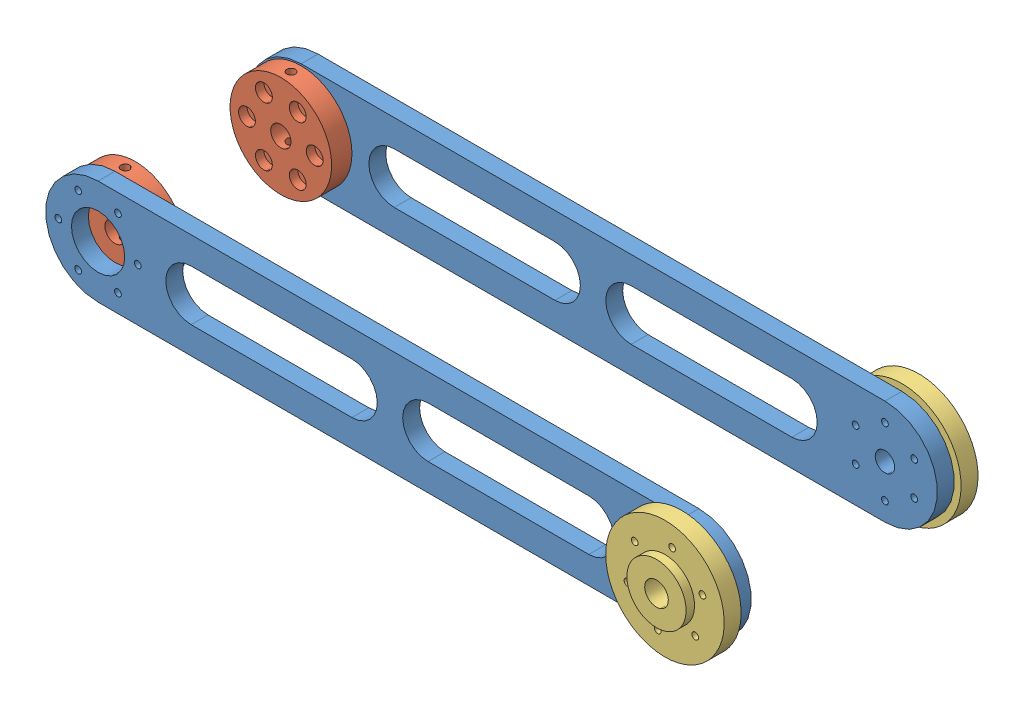
SolidWorks assembly khau2, configuration Default. Lengths in mm.
Overall size (425.35 98.68 160).
6 component instances, 3 part files, 11 mates.
Components (placement in the parent):
- khau2-1: khau2 [Default] at (105.1973 25.4543 -70.4266) x (1 -0.000341 0) z (-0.000341 -1 0) size (407 10 62)
- khau2-2: khau2 [Default] at (105.1973 25.4543 59.5734) x (1 -0.000341 0) z (0.000341 1 0) size (407 10 62)
- dem truc-1: dem truc [Default] at (0.6507 25.4899 49.5734) x (1 0 0) z (0 1 0) size (60 12 60)
- dem truc-2: dem truc [Default] at (0.6507 25.4899 -60.4266) x (1 0 0) z (0 -1 0) size (60 12 60)
- dem co dinh v2-1: dem co dinh v2 [Default] at (345.6506 25.3723 59.5734) x (0.648552 0.76117 0) z (0.76117 -0.648552 0) size (70 15 70)
- dem co dinh v2-2: dem co dinh v2 [Default] at (345.6506 25.3723 -70.4266) x (-0.635999 0.77169 0) z (-0.77169 -0.635999 0) size (70 15 70)
Mates (geometry in assembly coordinates):
- Concentric14: concentric: cylinder of assembly; cylinder of assembly; cylinder of khau2-1 through (345.6506 25.3723 -60.4266) axis (0 0 -1) radius 5.75; cylinder of dem co dinh v2-2 through (345.6506 25.3723 -85.4266) axis (0 0 1) radius 7
- Concentric15: concentric: cylinder of ? through (345.6506 25.3723 57.5734) axis (0 0 1) radius 5.75; cylinder of ? through (345.6506 25.3723 82.5734) axis (0 0 -1) radius 7
- Coincident12: coincident: plane of ? through (0.6507 25.4899 67.5734) normal (0 0 1); plane of ? through (345.6506 25.3723 67.5734) normal (0 0 -1)
- Coincident13: coincident: plane of assembly; plane of assembly; plane of khau2-1 through (0.6507 25.4899 -70.4266) normal (0 0 -1); plane of dem co dinh v2-2 through (345.6506 25.3723 -70.4266) normal (0 0 1)
- Concentric22: concentric: cylinder of ? through (0.6507 25.4899 57.5734) axis (0 0 1) radius 15.75; cylinder of ? through (0.6507 25.4899 45.5734) axis (0 0 1) radius 6
- Concentric23: concentric: cylinder of assembly; cylinder of assembly; cylinder of khau2-1 through (0.6507 25.4899 -60.4266) axis (0 0 -1) radius 15.75; cylinder of dem truc-2 through (0.6507 25.4899 -48.4266) axis (0 0 -1) radius 6
- Coincident14: coincident: plane of ? through (0.6507 25.4899 57.5734) normal (0 0 -1); plane of ? through (0.6507 25.4899 57.5734) normal (0 0 1)
- Coincident15: coincident: plane of assembly; plane of assembly; plane of khau2-1 through (0.6507 25.4899 -60.4266) normal (0 0 1); plane of dem truc-2 through (0.6507 25.4899 -60.4266) normal (0 0 -1)
- Distance2: distance = 110 mm: plane of assembly; plane of assembly; plane of khau2-2 through (0.6507 25.4899 49.5734) normal (0 0 -1); plane of khau2-1 through (0.6507 25.4899 -60.4266) normal (0 0 1)
- Concentric24: concentric: cylinder of ? through (345.6506 25.3723 82.5734) axis (0 0 -1) radius 7; cylinder of dem co dinh v2-2 through (345.6506 25.3723 -85.4266) axis (0 0 1) radius 7
- Concentric25: concentric: cylinder of ? through (0.6507 25.4899 45.5734) axis (0 0 1) radius 6; cylinder of dem truc-2 through (0.6507 25.4899 -48.4266) axis (0 0 -1) radius 6
